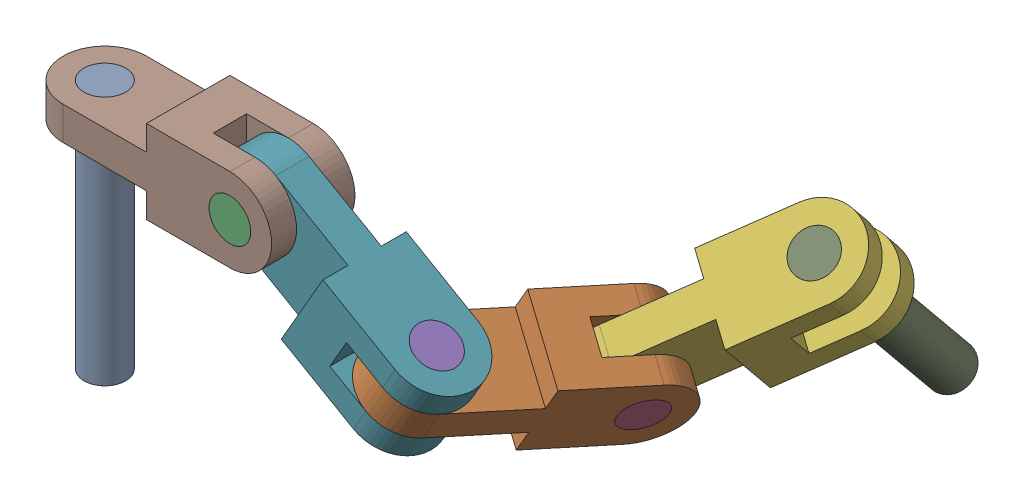
SolidWorks assembly Assem3 question (b), configuration Default. Lengths in mm.
Overall size (693.47 348.3 555.82).
9 component instances, 3 part files, 20 mates.
Components (placement in the parent):
- long_pin-1: long_pin [Default] at origin size (50 300 50)
- chain_link-1: chain_link [Default] at (409.8049 -141.1309 -90.6308) x (0.5 0.866025 0) z (-0.784886 0.453154 -0.422618) size (100 300 100)
- short_pin-1: short_pin [Default] at (200 -20 -50) x (1 0 0) z (0 1 0) size (50 100 50)
- short_pin-2: short_pin [Default] at (407.1604 -139.6041 -202.3925) x (0.594559 0.74285 -0.30769) z (-0.174511 0.492773 0.852479) size (50 100 50)
- short_pin-3: short_pin [Default] at (398.2051 -76.6987 0) x (0.866025 -0.5 0) z (0 0 1) size (50 100 50)
- chain_link-2: chain_link [Default] at (507.64 -115.9664 -245.3472) x (0.784886 -0.453154 0.422618) z (0.094754 0.761791 0.640856) size (100 300 100)
- chain_link-3: chain_link [Default] at (286.6025 -70 0) x (0 0 1) z (0.5 0.866025 0) size (100 300 100)
- chain_link-4: chain_link [Default] at (100 -20 0) x (0 -1 0) z (0 0 1) size (100 300 100)
- long_pin-2: long_pin [Default] at (573.613 -31.5814 -277.39) x (0.989711 -0.141414 0.021767) z (-0.107208 -0.6322 0.767352) size (50 300 50)
Mates (geometry in assembly coordinates):
- Concentric1: concentric anti-aligned: cylinder of long_pin-1 through (0 -300 0) axis (0 1 0) radius 25; cylinder of chain_link-4 through (0 30 0) axis (0 -1 0) radius 25
- Coincident1: coincident aligned: plane of long_pin-1 through (0 0 0) normal (0 1 0); plane of chain_link-4 through (0 0 0) normal (0 1 0)
- Lock1: lock: unknown of long_pin-1; unknown of chain_link-4
- Concentric2: concentric anti-aligned: cylinder of short_pin-1 through (200 -20 50) axis (0 0 -1) radius 25; cylinder of chain_link-4 through (200 -20 -50) axis (0 0 1) radius 25
- Coincident2: coincident aligned: plane of short_pin-1 through (200 -20 50) normal (0 0 1); plane of chain_link-4 through (200 -20 50) normal (0 0 1)
- Concentric3: concentric anti-aligned: cylinder of short_pin-1 through (200 -20 50) axis (0 0 -1) radius 25; cylinder of chain_link-3 through (200 -20 -50) axis (0 0 1) radius 25
- Coincident3: coincident anti-aligned: plane of chain_link-3 through (200 -20 -20) normal (0 0 -1); plane of chain_link-4 through (250 30 -20) normal (0 0 1)
- Angle2: planar angle = 0.523599 rad aligned: plane of chain_link-4 through (100 30 50) normal (0 1 0); plane of chain_link-3 through (398.2051 -76.6987 0) normal (0.5 0.866025 0)
- Concentric4: concentric aligned: cylinder of short_pin-3 through (348.2051 -163.3013 0) axis (0.5 0.866025 0) radius 25; cylinder of chain_link-3 through (348.2051 -163.3013 0) axis (0.5 0.866025 0) radius 25
- Coincident10: coincident aligned: plane of short_pin-3 through (398.2051 -76.6987 0) normal (0.5 0.866025 0); plane of chain_link-3 through (398.2051 -76.6987 0) normal (0.5 0.866025 0)
- Concentric5: concentric aligned: cylinder of chain_link-1 through (348.2051 -163.3013 0) axis (0.5 0.866025 0) radius 25; cylinder of short_pin-3 through (348.2051 -163.3013 0) axis (0.5 0.866025 0) radius 25
- Coincident11: coincident anti-aligned: plane of chain_link-1 through (383.2051 -102.6795 0) normal (0.5 0.866025 0); plane of chain_link-3 through (426.5064 -127.6795 -50) normal (-0.5 -0.866025 0)
- Angle3: planar angle = 2.007129 rad anti-aligned: plane of chain_link-3 through (311.6025 -26.6987 -50) normal (0 0 -1); plane of chain_link-1 through (407.1604 -139.6041 -202.3925) normal (-0.784886 0.453154 -0.422618)
- Concentric6: concentric aligned: cylinder of chain_link-1 through (485.649 -184.9195 -160.1306) axis (-0.784886 0.453154 -0.422618) radius 25; cylinder of short_pin-2 through (485.649 -184.9195 -160.1306) axis (-0.784886 0.453154 -0.422618) radius 25
- Coincident13: coincident aligned: plane of chain_link-1 through (407.1604 -139.6041 -202.3925) normal (-0.784886 0.453154 -0.422618); plane of short_pin-2 through (407.1604 -139.6041 -202.3925) normal (-0.784886 0.453154 -0.422618)
- Concentric7: concentric anti-aligned: cylinder of short_pin-2 through (485.649 -184.9195 -160.1306) axis (-0.784886 0.453154 -0.422618) radius 25; cylinder of chain_link-2 through (407.1604 -139.6041 -202.3925) axis (0.784886 -0.453154 0.422618) radius 25
- Coincident14: coincident anti-aligned: plane of chain_link-1 through (455.4023 -225.1916 -218.1246) normal (-0.784886 0.453154 -0.422618); plane of chain_link-2 through (462.1024 -171.3249 -172.8092) normal (0.784886 -0.453154 0.422618)
- Angle4: planar angle = 2.356194 rad anti-aligned: plane of chain_link-2 through (573.613 -31.5814 -277.39) normal (0.094754 0.761791 0.640856); plane of chain_link-1 through (395.5606 -75.1719 -111.7617) normal (0.5 0.866025 0)
- Concentric8: concentric aligned: cylinder of chain_link-2 through (396.8363 -337.7677 -277.39) axis (0.612353 0.462954 -0.640856) radius 25; cylinder of long_pin-2 through (274.3657 -430.3585 -149.2187) axis (0.612353 0.462954 -0.640856) radius 25
- Coincident16: coincident aligned: plane of chain_link-2 through (458.0716 -291.4722 -341.4757) normal (0.612353 0.462954 -0.640856); plane of long_pin-2 through (458.0716 -291.4722 -341.4757) normal (0.612353 0.462954 -0.640856)
